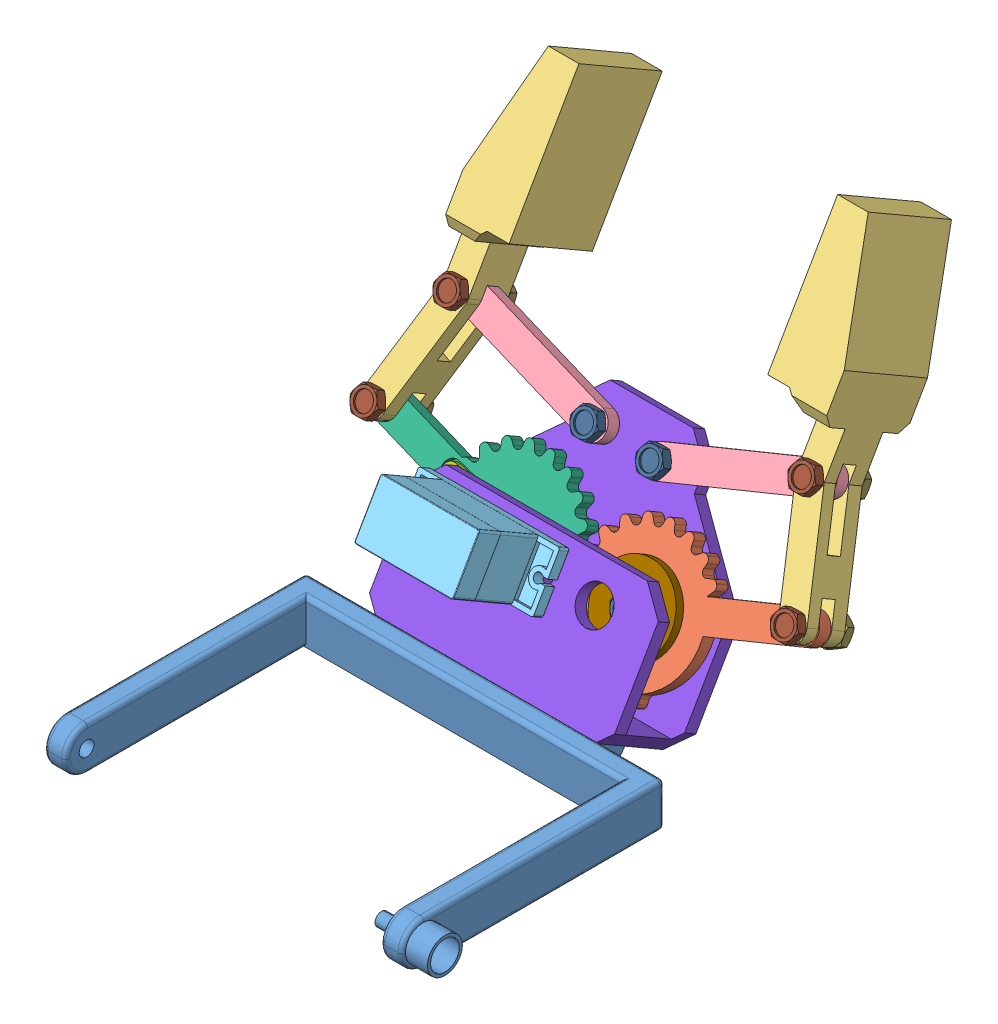
SolidWorks assembly arm1, configuration Default. Lengths in mm.
Overall size (110.02 107.88 131.32).
27 component instances, 13 part files, 3 mates.
Components (placement in the parent):
- arm-2: arm [Default] at (-24.8916 55.9585 30.1716) size (87 10 66.93)
- Assembly 2.0 upload.stp-2: Assembly 2.0 upload.stp [Default] at (-62.3508 78.3564 -62.8111) x (0 -0.866025 0.5) z (-1 0 0) size (99.56 43.3 110.02)
  - gear.stp-1: gear.stp [Default] at (1.3043 -4.9957 -15) x (0.330984 0 0.943636) z (-0.943636 0 0.330984) size (53 3 32)
  - gripper.stp-1: gripper.stp [Default] at (-7.3079 -8.4957 47.6327) size (71 22 21.5)
  - tuas.stp-1: tuas.stp [Default] at (-30.3079 -1.9957 40.1327) x (-0.966894 0 -0.255178) z (-0.255178 0 0.966894) size (6.5 3 40.25)
  - gripper.stp-2: gripper.stp [Default] at (-9.8664 1.0043 -46.8477) x (1 0 0) z (0 0 -1) size (71 22 21.5)
  - tuas.stp-2: tuas.stp [Default] at (-32.8664 -1.9957 -39.3477) x (0.943636 0 -0.330984) z (-0.330984 0 -0.943636) size (6.5 3 40.25)
  - microservoSG90.stp-1: microservoSG90.stp [Default] at (1.3043 28.3043 9.9) x (0 0 -1) z (-1 0 0) size (32.3 29.8 12.41)
  - gear 2.1.stp-1: gear 2.1.stp [Default] at (1.3043 -1.9957 15) x (0.255178 0 -0.966894) z (-0.966894 0 -0.255178) size (52.85 3 31.7)
  - servo horn 1 v2.stp-1: servo horn 1 v2.stp [Default] at (1.3043 -1.4957 15) x (-0.966894 0 -0.255178) z (-0.255178 0 0.966894) size (7.2 3.7 21.2)
  - base 2.0 upload.stp-1: base 2.0 upload.stp [Default] at (28.3043 -7.9957 35) size (50 18.1 60)
  - Gear Ring.stp-1: Gear Ring.stp [Default] at (1.3043 -1.7957 -15) x (-0.620589 0 -0.784136) z (0.784136 0 -0.620589) size (18 2 18)
  - AS 1427 - M3 x 10.stp-1: AS 1427 - M3 x 10.stp [Default] at (1.3043 0.2043 -15) x (0 -1 0) z (0 0 1) size (12.33 5.5 6.35)
  - AS 1427 - M3 x 10.stp-2: AS 1427 - M3 x 10.stp [Default] at (-21.6957 -1.9957 -7.5) x (0 -1 0) z (0 0 1) size (12.33 5.5 6.35)
  - AS 1427 - M3 x 10.stp-3: AS 1427 - M3 x 10.stp [Default] at (-21.6957 -1.9957 7.5) x (0 -1 0) z (0 0 1) size (12.33 5.5 6.35)
  - AS 1427 - M3 x 12.stp-1: AS 1427 - M3 x 12.stp [Default] at (-9.8664 1.0043 -46.8477) x (0 -1 0) z (0 0 1) size (14.33 5.5 6.35)
  - AS 1427 - M3 x 12.stp-2: AS 1427 - M3 x 12.stp [Default] at (-32.8664 1.0043 -39.3477) x (0 -1 0) z (0 0 1) size (14.33 5.5 6.35)
  - AS 1427 - M3 x 12.stp-3: AS 1427 - M3 x 12.stp [Default] at (-7.3079 1.5043 47.6327) x (0 -1 0) z (0 0 1) size (14.33 5.5 6.35)
  - AS 1427 - M3 x 12.stp-4: AS 1427 - M3 x 12.stp [Default] at (-30.3079 1.5043 40.1327) x (0 -1 0) z (0 0 1) size (14.33 5.5 6.35)
  - AS 1112 - M3,5.stp-1: AS 1112 - M3,5.stp [Default] at (1.3043 -10.0957 -15) x (0 1 0) z (0 0 1) size (2.1 6.93 6)
  - AS 1112 - M3,5.stp-2: AS 1112 - M3,5.stp [Default] at (-21.6957 -10.0957 -7.5) x (0 1 0) z (0 0 1) size (2.1 6.93 6)
  - AS 1112 - M3,5.stp-3: AS 1112 - M3,5.stp [Default] at (-21.6957 -10.0957 7.5) x (0 1 0) z (0 0 1) size (2.1 6.93 6)
  - AS 1112 - M3,5.stp-4: AS 1112 - M3,5.stp [Default] at (-32.8664 -11.0957 -39.3477) x (0 1 0) z (0 0 1) size (2.1 6.93 6)
  - AS 1112 - M3,5.stp-5: AS 1112 - M3,5.stp [Default] at (-9.8664 -11.0957 -46.8477) x (0 1 0) z (0 0 1) size (2.1 6.93 6)
  - AS 1112 - M3,5.stp-6: AS 1112 - M3,5.stp [Default] at (-30.3079 -10.5957 40.1327) x (0 1 0) z (0 0 1) size (2.1 6.93 6)
  - AS 1112 - M3,5.stp-7: AS 1112 - M3,5.stp [Default] at (-7.3079 -10.5957 47.6327) x (0 1 0) z (0 0 1) size (2.1 6.93 6)
  - ISO 7046-1 - M1,6 x 8 - 4.8 - H.stp-1: ISO 7046-1 - M1,6 x 8 - 4.8 - H.stp [Default] at (1.3043 -5.9957 15) x (0 1 0) z (0 0 1) size (8 3 3)
Mates (geometry in assembly coordinates):
- Coincident3: coincident anti-aligned: plane of arm-2 through (-24.8916 60.4585 -51.2025) normal (0 0.866025 -0.5); plane of Assembly 2.0 upload.stp-2/base 2.0 upload.stp-1 through (-87.3508 55.9085 -59.0833) normal (0 -0.866025 0.5)
- Coincident5: coincident: line of arm-2 through (-87.3508 60.9585 -50.3365) axis (0 0.5 0.866025); plane of Assembly 2.0 upload.stp-2/base 2.0 upload.stp-1 through (-92.3508 60.2386 -61.5833) normal (-0.707107 -0.612372 0.353553)
- Coincident6: coincident aligned: line of arm-2 through (-87.3508 64.9585 -43.4083) axis (1 0 0); line of Assembly 2.0 upload.stp-2/base 2.0 upload.stp-1 through (-87.3508 64.9585 -43.4083) axis (1 0 0)
